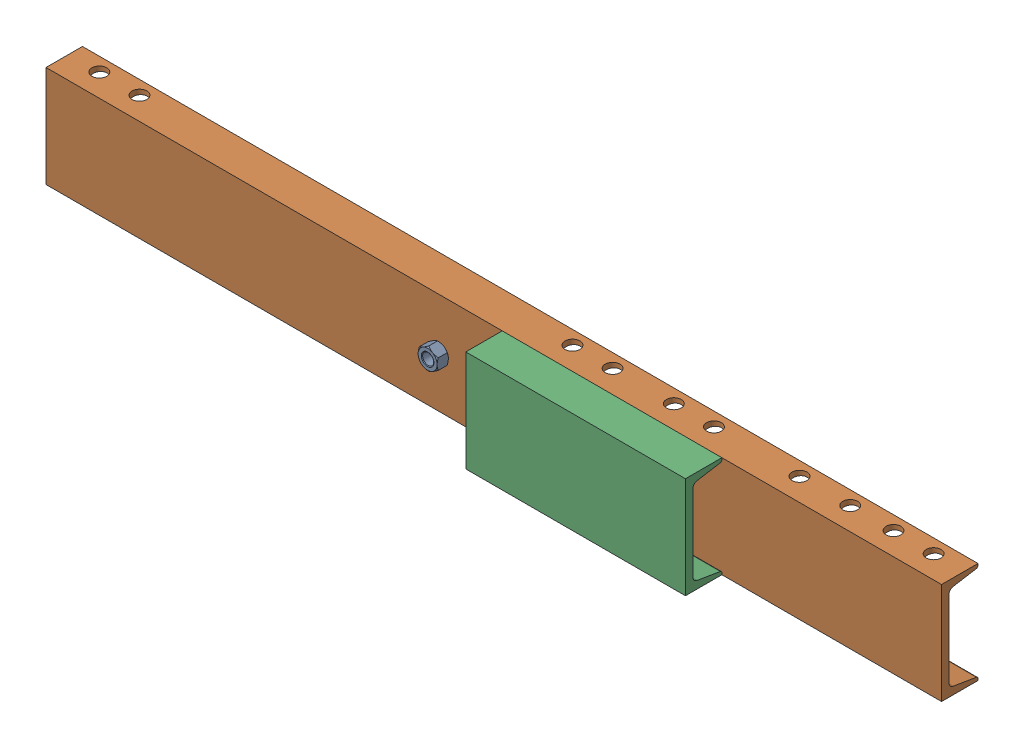
SolidWorks assembly 01-116-00-0, configuration Default. Lengths in mm.
Overall size (1346.2 152.4 109.58).
3 component instances, 3 part files, 0 mates.
Components (placement in the parent):
- hex nut_ai(HNUT 0.7500-10-D-C)-1: hex nut_ai(HNUT 0.7500-10-D-C) [Default] at (-82.55 0 44.2849) size (28.57 33 16.89)
- 01-115-00-0-1: 01-115-00-0 [Default] at origin size (1346.2 152.4 54.79)
- 01-034-00-0-1: 01-034-00-0 [Default] at (177.8 0 54.7878) size (330.2 152.4 54.79)
